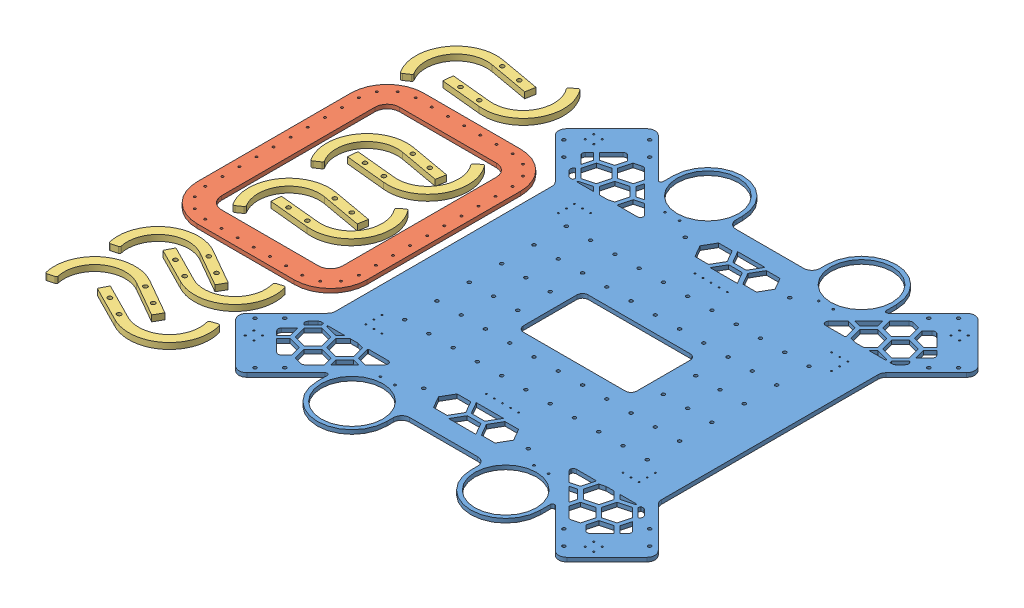
SolidWorks assembly 0.25 Plate Layout_Feb 2020, configuration Default. Lengths in mm.
Overall size (914.4 17.46 1219.2).
12 component instances, 3 part files, 8 mates.
Components (placement in the parent):
- MS-P-0008-Frame, Base Plate-1: MS-P-0008-Frame, Base Plate [Waterjet] at origin size (653.22 6.35 668.02)
- MS-P-0017-Enclosure, Window Frame-1: MS-P-0017-Enclosure, Window Frame [Default] at (-407.4924 -6.35 -18.2765) x (0.000322 0 -1) z (1 0 0.000322) size (355.6 6.35 266.7)
- MS-P-0011-Thruster, Horizontal Guard-1: MS-P-0011-Thruster, Horizontal Guard [Default] at (-387.5839 0 -106.5884) x (-0.995176 0 -0.09811) z (0 -1 0) size (127 107.31 9.53)
- MS-P-0011-Thruster, Horizontal Guard-3: MS-P-0011-Thruster, Horizontal Guard [Default] at (-428.2893 0 -51.6051) x (0.984315 0 0.176422) z (0 -1 0) size (127 107.31 9.53)
- MS-P-0011-Thruster, Horizontal Guard-6: MS-P-0011-Thruster, Horizontal Guard [Default] at (-427.2343 1.5875 71.9218) x (0.984315 0 0.176422) z (0 -1 0) size (127 107.31 9.53)
- MS-P-0011-Thruster, Horizontal Guard-7: MS-P-0011-Thruster, Horizontal Guard [Default] at (-385.4959 1.5875 15.6092) x (-0.995176 0 -0.09811) z (0 -1 0) size (127 107.31 9.53)
- MS-P-0011-Thruster, Horizontal Guard-8: MS-P-0011-Thruster, Horizontal Guard [Default] at (-465.8768 0 238.7745) x (0.867512 0 0.497417) z (0 -1 0) size (127 107.31 9.53)
- MS-P-0011-Thruster, Horizontal Guard-9: MS-P-0011-Thruster, Horizontal Guard [Default] at (-389.1242 0 194.7004) x (-0.891635 0 -0.452755) z (0 -1 0) size (127 107.31 9.53)
- MS-P-0011-Thruster, Horizontal Guard-10: MS-P-0011-Thruster, Horizontal Guard [Default] at (-479.4047 -4.7625 324.682) x (0.867512 0 0.497417) z (0 -1 0) size (127 107.31 9.53)
- MS-P-0011-Thruster, Horizontal Guard-11: MS-P-0011-Thruster, Horizontal Guard [Default] at (-393.6907 -4.7625 293.1281) x (-0.891635 0 -0.452755) z (0 -1 0) size (127 107.31 9.53)
- MS-P-0011-Thruster, Horizontal Guard-12: MS-P-0011-Thruster, Horizontal Guard [Default] at (-478.6351 -1.5875 -242.4207) x (0.984315 0 0.176422) z (0 -1 0) size (127 107.31 9.53)
- MS-P-0011-Thruster, Horizontal Guard-13: MS-P-0011-Thruster, Horizontal Guard [Default] at (-412.7099 3.175 -281.5491) x (-0.995176 0 -0.09811) z (0 -1 0) size (127 107.31 9.53)
Mates (geometry in assembly coordinates):
- Coincident1: coincident aligned: plane of MS-P-0008-Frame, Base Plate-1 through (0 0 0) normal (1 0 0)
- Coincident2: coincident aligned: plane of MS-P-0008-Frame, Base Plate-1 through (0 0 0) normal (0 1 0)
- Coincident3: coincident aligned: plane of MS-P-0008-Frame, Base Plate-1 through (0 0 0) normal (0 0 1)
- Coincident5: coincident aligned: plane of MS-P-0008-Frame, Base Plate-1 through (0 0 0) normal (0 1 0); plane of MS-P-0017-Enclosure, Window Frame-1 through (-407.4924 0 -18.2765) normal (0 1 0)
- Coincident6: coincident aligned: plane of MS-P-0008-Frame, Base Plate-1 through (0 0 0) normal (0 1 0); plane of MS-P-0011-Thruster, Horizontal Guard-1 through (-338.8874 0 -143.2595) normal (0 1 0)
- Coincident8: coincident aligned: plane of MS-P-0008-Frame, Base Plate-1 through (0 0 0) normal (0 1 0); plane of MS-P-0011-Thruster, Horizontal Guard-3 through (-479.7307 0 -18.8957) normal (0 1 0)
- Coincident12: coincident aligned: plane of MS-P-0008-Frame, Base Plate-1 through (0 0 0) normal (0 1 0); plane of MS-P-0011-Thruster, Horizontal Guard-9 through (-330.436 0 178.2134) normal (0 1 0)
- Coincident13: coincident aligned: plane of MS-P-0008-Frame, Base Plate-1 through (0 0 0) normal (0 1 0); plane of MS-P-0011-Thruster, Horizontal Guard-8 through (-525.326 0 252.2622) normal (0 1 0)
